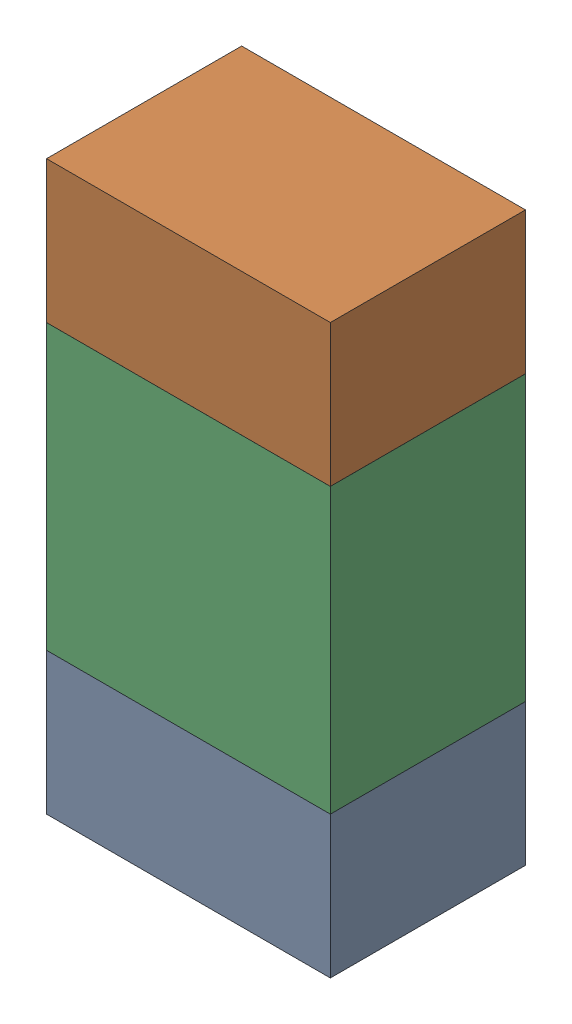
SolidWorks assembly R40, configuration ﾃﾞﾌｫﾙﾄ. Lengths in mm.
Overall size (0.8 1.6 0.55).
6 component instances, 2 part files, 0 mates.
Components (placement in the parent):
- 689261784-1: 689261784 [ﾃﾞﾌｫﾙﾄ] at (46.0376 15.2751 -1.7503) size (0.8 0.4 0.55)
  - Extruded_34-1: Extruded_34 [ﾃﾞﾌｫﾙﾄ] at origin size (0.8 0.4 0.55)
- 689261784-2: 689261784 [ﾃﾞﾌｫﾙﾄ] at (46.0376 16.4751 -1.7503) size (0.8 0.4 0.55)
  - Extruded_34-1: Extruded_34 [ﾃﾞﾌｫﾙﾄ] at origin size (0.8 0.4 0.55)
- 689261648-1: 689261648 [ﾃﾞﾌｫﾙﾄ] at (46.0376 15.875 -1.7503) size (0.8 0.8 0.55)
  - Extruded_33-1: Extruded_33 [ﾃﾞﾌｫﾙﾄ] at origin size (0.8 0.8 0.55)
